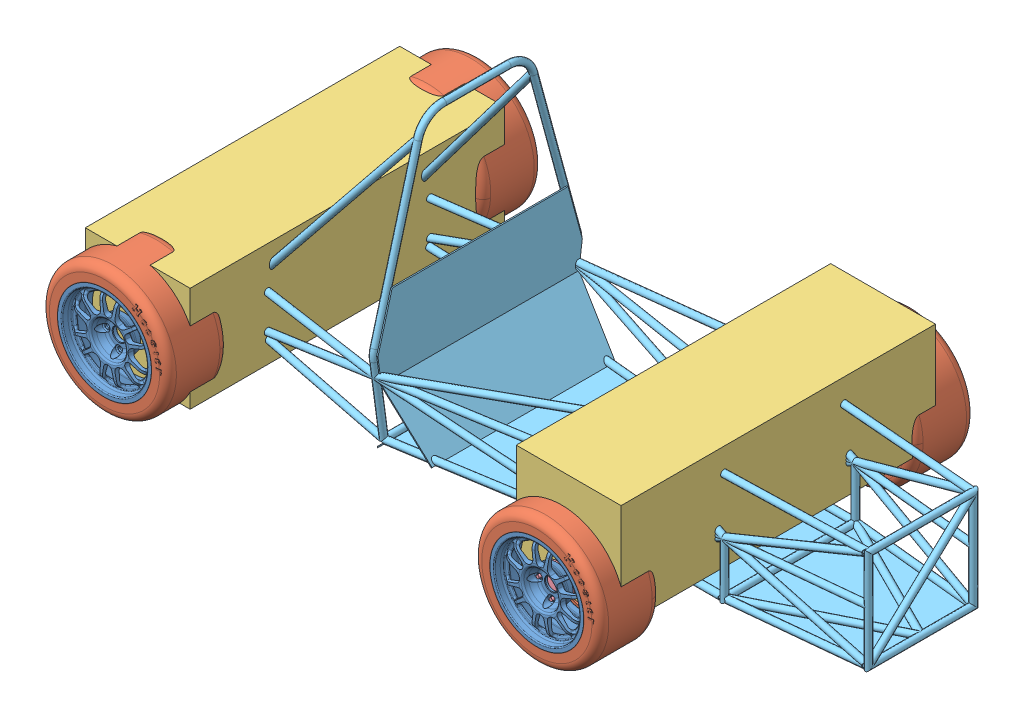
SolidWorks assembly vehicle dynamics platform, configuration Default. Lengths in mm.
Overall size (2669.33 1119.33 1432).
17 component instances, 5 part files, 8 mates.
Components (placement in the parent):
- Wheel and Tire Assembly-1: Wheel and Tire Assembly [Default] at (-25.7028 331.0601 426.8604) size (484.14 484.14 231.18)
  - OZ Al 7x13 Wheel-1: OZ Al 7x13 Wheel [Default] at (0 0 19.8) x (-1 0 0) z (0 0 1) size (359.65 359.65 190.61)
  - Hoosier 20.5x7x13 R25B A2500 Tire-2: Hoosier 20.5x7x13 R25B A2500 Tire [Default] at origin size (484.14 484.14 231.18)
- Assem3^vehicle dynamics platform-1: Assem3^vehicle dynamics platform [Default] at (1624.2972 331.0601 426.8604) size (484.14 595.56 1295.76) (virtual)
  - Wheel and Tire Assembly-1: Wheel and Tire Assembly [Default] at origin size (484.14 484.14 231.18)
    - OZ Al 7x13 Wheel-1: OZ Al 7x13 Wheel [Default] at (0 0 19.8) x (-1 0 0) z (0 0 1) size (359.65 359.65 190.61)
    - Hoosier 20.5x7x13 R25B A2500 Tire-2: Hoosier 20.5x7x13 R25B A2500 Tire [Default] at origin size (484.14 484.14 231.18)
  - designbox-1: designbox [Default] at (26.7344 153.4894 -1179.7618) size (400 400 1200)
  - HUB-PROTOTYPE-2: HUB-PROTOTYPE [Default] at (0 0 49.8) x (0 -1 0) z (0 0 -1) size (126 126 28)
- Wheel and Tire Assembly-3: Wheel and Tire Assembly [Default] at (-25.7028 331.0601 -773.1396) x (-0.998016 0.062963 0) z (0 0 -1) size (484.14 484.14 231.18)
  - OZ Al 7x13 Wheel-1: OZ Al 7x13 Wheel [Default] at (0 0 19.8) x (-1 0 0) z (0 0 1) size (359.65 359.65 190.61)
  - Hoosier 20.5x7x13 R25B A2500 Tire-2: Hoosier 20.5x7x13 R25B A2500 Tire [Default] at origin size (484.14 484.14 231.18)
- Wheel and Tire Assembly-4: Wheel and Tire Assembly [Default] at (1624.2972 331.0601 -773.1396) x (-1 0 0) z (0 0 -1) size (484.14 484.14 231.18)
  - OZ Al 7x13 Wheel-1: OZ Al 7x13 Wheel [Default] at (0 0 19.8) x (-1 0 0) z (0 0 1) size (359.65 359.65 190.61)
  - Hoosier 20.5x7x13 R25B A2500 Tire-2: Hoosier 20.5x7x13 R25B A2500 Tire [Default] at origin size (484.14 484.14 231.18)
- Copy of Chassis-1: Copy of Chassis [Default<As Machined>] at (674.2972 181.0601 -174.2825) x (0 0 -1) z (1 0 0) size (801.43 1041.37 2575)
- designbox-2: designbox [Default] at (-9.5447 364.733 -768.7382) size (400 400 1200)
Mates (geometry in assembly coordinates):
- Concentric1: concentric anti-aligned: cylinder of Wheel and Tire Assembly-1/OZ Al 7x13 Wheel-1 through (-25.7028 331.0601 470.0104) axis (0 0 1) radius 25; cylinder of Wheel and Tire Assembly-3/OZ Al 7x13 Wheel-1 through (-25.7028 331.0601 -816.2896) axis (0 0 -1) radius 25
- Coincident3: coincident aligned: plane of Wheel and Tire Assembly-3/Hoosier 20.5x7x13 R25B A2500 Tire-2 through (-251.1819 132.3426 -888.1396) normal (0 0 -1); plane of Wheel and Tire Assembly-4/Hoosier 20.5x7x13 R25B A2500 Tire-2 through (1411.7772 118.5401 -888.1396) normal (0 0 -1)
- Distance2: distance = 115 mm: plane of Wheel and Tire Assembly-4/Hoosier 20.5x7x13 R25B A2500 Tire-2 through (1411.7772 118.5401 -888.1396) normal (0 0 -1); point of assembly
- Concentric4: concentric anti-aligned: cylinder of Wheel and Tire Assembly-3/OZ Al 7x13 Wheel-1 through (-25.7028 331.0601 -816.2896) axis (0 0 -1) radius 25; line of Copy of Chassis-1 through (-25.7028 331.0601 -474.2825) axis (0 0 1)
- Parallel4: parallel aligned: line of assembly; line of Copy of Chassis-1 through (-175.7028 406.0601 -474.2825) axis (1 0 0)
- Concentric5: concentric: cylinder of Assem3^vehicle dynamics platform-1/Wheel and Tire Assembly-1/OZ Al 7x13 Wheel-1 through (1624.2972 331.0601 470.0104) axis (0 0 1) radius 25
- Concentric6: concentric anti-aligned: cylinder of Assem3^vehicle dynamics platform-1/Wheel and Tire Assembly-1/OZ Al 7x13 Wheel-1 through (1624.2972 331.0601 470.0104) axis (0 0 1) radius 25; cylinder of Wheel and Tire Assembly-4/OZ Al 7x13 Wheel-1 through (1624.2972 331.0601 -816.2896) axis (0 0 -1) radius 25
- Coincident10: coincident aligned: plane of Wheel and Tire Assembly-1/Hoosier 20.5x7x13 R25B A2500 Tire-2 through (186.8172 118.5401 541.8604) normal (0 0 1); plane of Assem3^vehicle dynamics platform-1/Wheel and Tire Assembly-1/Hoosier 20.5x7x13 R25B A2500 Tire-2 through (1836.8172 118.5401 541.8604) normal (0 0 1)
